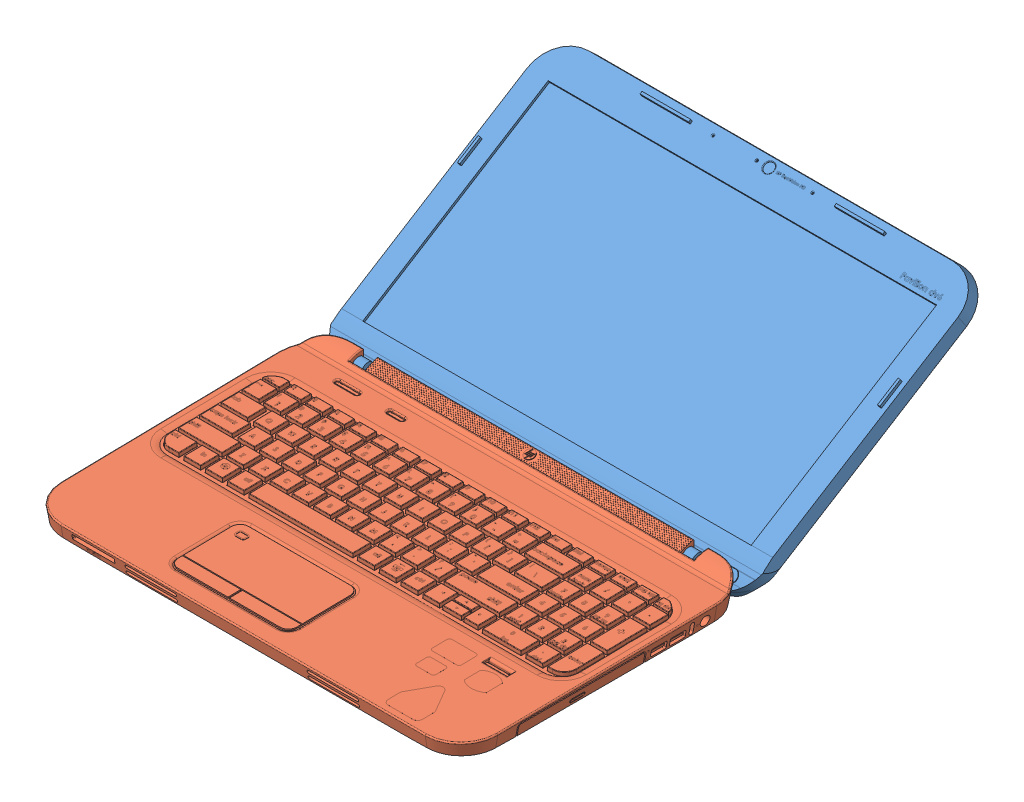
SolidWorks assembly Assem1, configuration Default. Lengths in mm.
Overall size (181.6 76.33 235.2).
2 component instances, 2 part files, 3 mates.
Components (placement in the parent):
- Part1-1: Part1 [Default] at (-36.722 26.2874 -135.5738) x (1 0 0) z (0 0.848799 0.528715) size (180 120.54 13.7)
- Part 2-1: Part 2 [Default] at origin size (181.6 16.82 164.03)
Mates (geometry in assembly coordinates):
- Concentric1: concentric aligned: circle of Part1-1; circle of Part 2-1
- Concentric2: concentric anti-aligned: circle of Part 2-1; circle of Part1-1
- Distance1: distance = 4.6034 mm aligned: plane of Part1-1 through (33.278 4.0758 -78.964) normal (1 0 0); plane of Part 2-1 through (28.6746 4.9996 -86.4921) normal (1 0 0)
